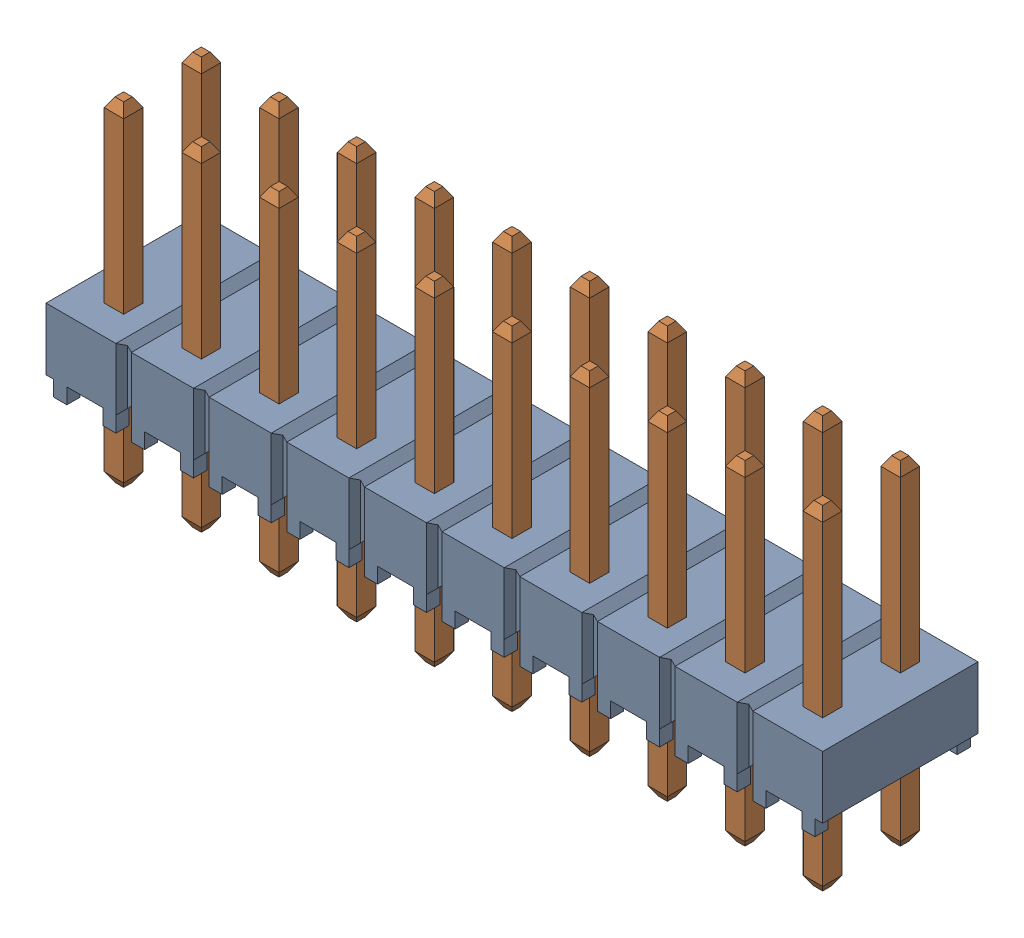
SolidWorks assembly TSW_110_07_G_D, configuration Default. Lengths in mm.
Overall size (25.4 10.92 5.08).
2 component instances, 2 part files, 0 mates.
Components (placement in the parent):
- _TSW_110_07_G_D_body_2-1: _TSW_110_07_G_D_body_2 [Default] at origin size (25.4 2.54 5.08)
- _T_1S6_07_TSW_1_07_10_D_4-1: _T_1S6_07_TSW_1_07_10_D_4 [Default] at (0 -2.54 0) size (23.75 10.92 3.43)
